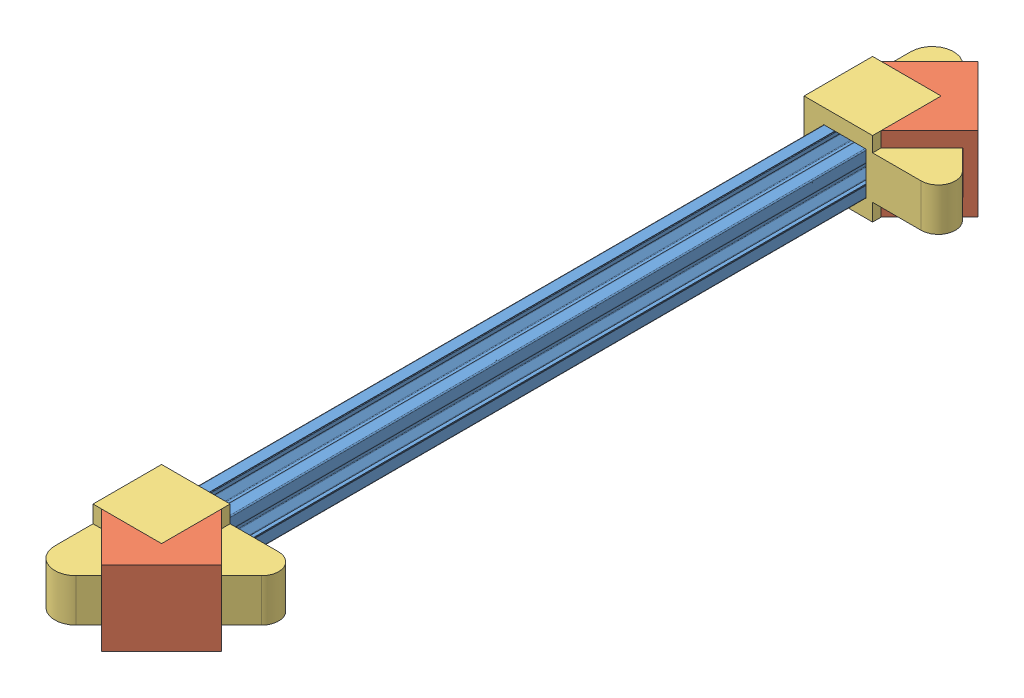
SolidWorks assembly Assem3, configuration Varsayılan. Lengths in mm.
Overall size (93.47 36.01 453.33).
7 component instances, 3 part files, 6 mates.
Components (placement in the parent):
- sigma_20x20x1000-1: sigma_20x20x1000 [Varsayılan] at (-144.7646 -85.6017 253.4901) x (0 0 -1) z (1 -0.000076 0) size (350 20 20)
- motortutucular-1: motortutucular [Varsayılan] at (-103.5623 -84.2375 280.9722) x (0.707107 -0.000054 -0.707107) z (-0.707107 0.000054 -0.707107) size (86.65 35 86.65)
  - motortutucuarka-1: motortutucuarka [Varsayılan] at (-25.258 -13.6326 22.249) size (39.6 35 31.98)
  - motortutucuon-1: motortutucuon [Varsayılan] at (-0.4565 -8.6326 49.0416) x (-0.707107 0 0.707107) z (0 1 0) size (62.69 59.86 35)
- motortutucular-2: motortutucular [Varsayılan] at (-103.5625 -86.9722 -123.9919) x (0.707107 -0.000054 0.707107) z (-0.707107 0.000054 0.707107) size (86.65 35 86.65)
  - motortutucuarka-1: motortutucuarka [Varsayılan] at (-25.258 -13.6326 22.249) size (39.6 35 31.98)
  - motortutucuon-1: motortutucuon [Varsayılan] at (-0.4565 -8.6326 49.0416) x (-0.707107 0 0.707107) z (0 1 0) size (62.69 59.86 35)
Mates (geometry in assembly coordinates):
- Coincident1: coincident anti-aligned: plane of sigma_20x20x1000-1 through (-137.9071 -80.4522 -96.5099) normal (0 0 -1); plane of motortutucular-2/motortutucuon-1 through (-138.562 -75.6022 -96.5099) normal (0 0 1)
- Coincident3: coincident anti-aligned: line of sigma_20x20x1000-1 through (-154.2639 -75.601 -96.5099) axis (1 -0.000076 0); line of motortutucular-2/motortutucuon-1 through (-134.7639 -75.6025 -96.5099) axis (-1 0.000076 0)
- Coincident4: coincident anti-aligned: line of sigma_20x20x1000-1 through (-154.7643 -80.9509 -96.5099) axis (0.000076 1 0); line of motortutucular-2/motortutucuon-1 through (-154.7639 -75.6009 -96.5099) axis (-0.000076 -1 0)
- Coincident5: coincident anti-aligned: plane of sigma_20x20x1000-1 through (-137.9071 -80.4522 253.4901) normal (0 0 1); plane of motortutucular-1/motortutucuon-1 through (-138.5635 -95.6022 253.4901) normal (0 0 -1)
- Coincident6: coincident aligned: line of sigma_20x20x1000-1 through (-149.4154 -95.6013 253.4901) axis (-1 0.000076 0); line of motortutucular-1/motortutucuon-1 through (-134.7654 -95.6025 253.4901) axis (-1 0.000076 0)
- Coincident7: coincident anti-aligned: line of sigma_20x20x1000-1 through (-134.7639 -76.1025 253.4901) axis (-0.000076 -1 0); line of motortutucular-1/motortutucuon-1 through (-134.7654 -95.6025 253.4901) axis (0.000076 1 0)
